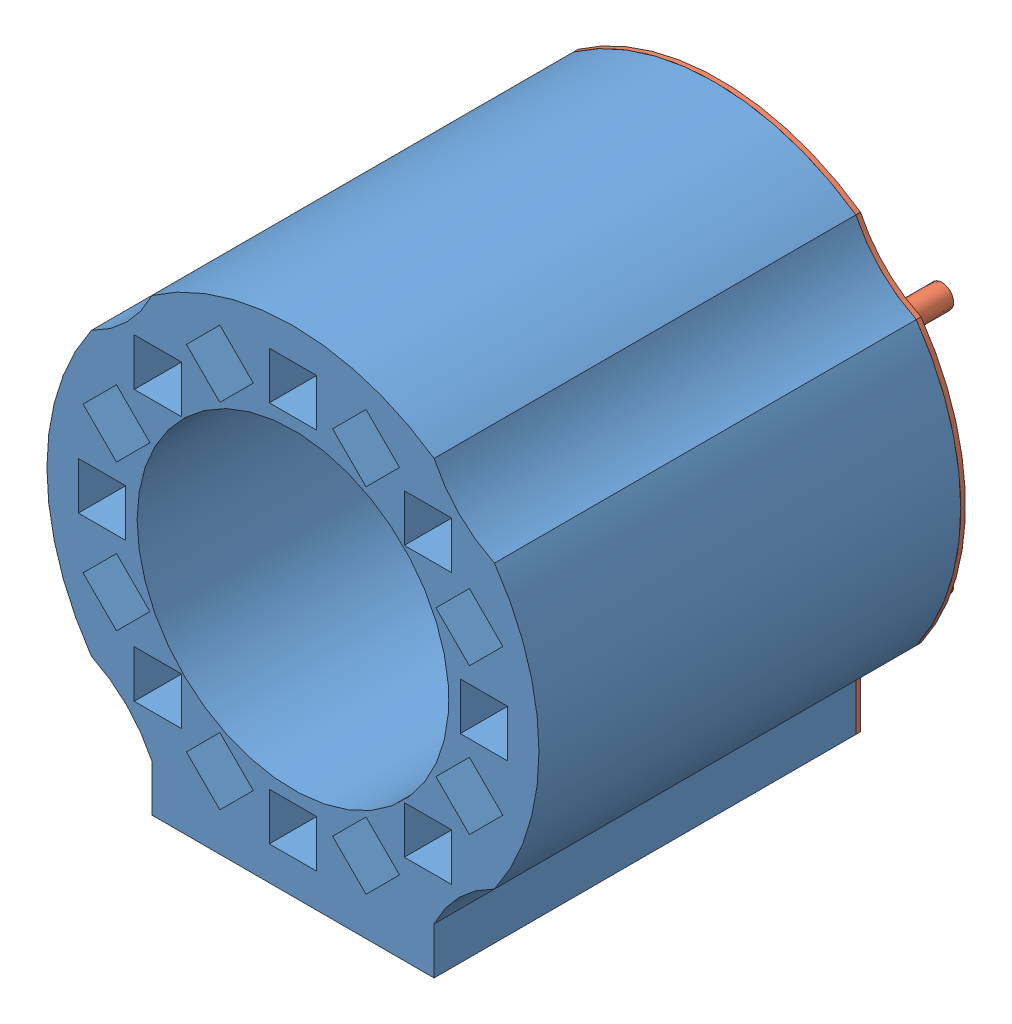
SolidWorks assembly Assem2, configuration Default. Lengths in mm.
Overall size (105 105.51 101).
2 component instances, 2 part files, 1 mates.
Components (placement in the parent):
- outside_ring-1: outside_ring [Default] at (11.7274 48.3118 100.1613) size (105 105.51 90)
- outside_ring_cap-1: outside_ring_cap [Default] at (11.7274 48.3118 99.1613) size (105 105.51 11)
Mates (geometry in assembly coordinates):
- Coincident1: coincident: circle of outside_ring-1; circle of outside_ring_cap-1
